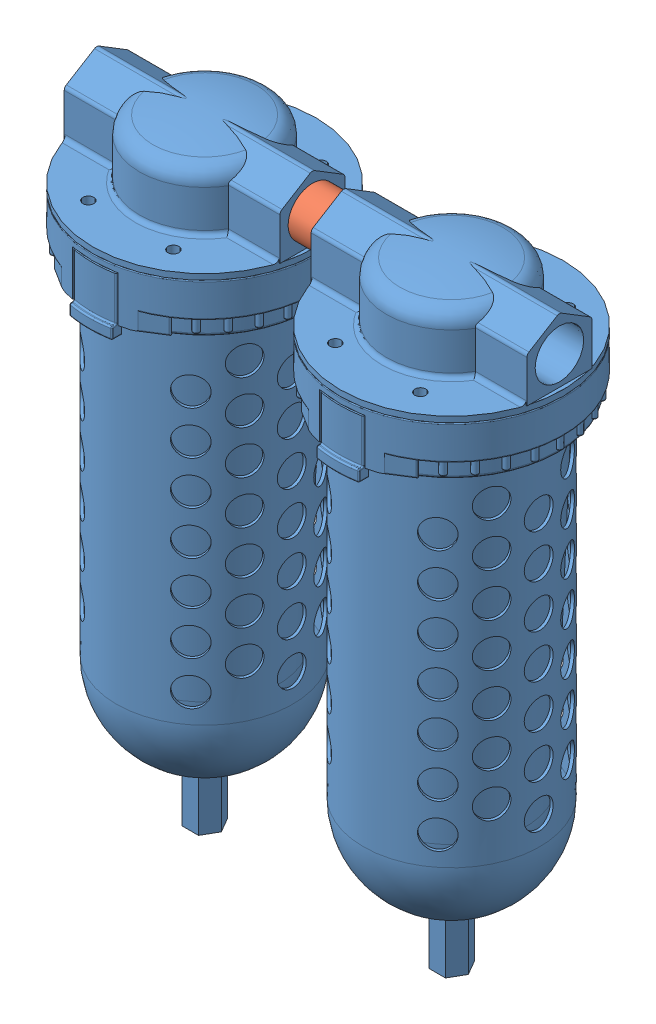
SolidWorks assembly ReadingTech_4P-060-P04-DC, configuration Default. Lengths in mm.
Overall size (206.63 271.66 99.95).
3 component instances, 2 part files, 3 mates.
Components (placement in the parent):
- ReadingTech_3P060P04F-1: ReadingTech_3P060P04F [Default] at (-33.0064 -72.8295 0.9918) size (98.17 271.66 99.95)
- ReadingTech_3P060P04F-2: ReadingTech_3P060P04F [Default] at (75.4516 -72.8295 0.9918) size (98.17 271.66 99.95)
- ReadingTech- 60cfm_connector_.5in-1: ReadingTech- 60cfm_connector_.5in [Default] at (28.0806 143.0705 0.9918) x (0 1 0) z (0 0 1) size (21.34 13.72 21.34)
Mates (geometry in assembly coordinates):
- Coincident1: coincident anti-aligned: circle of ReadingTech_3P060P04F-1; circle of ReadingTech- 60cfm_connector_.5in-1
- Coincident2: coincident aligned: circle of ReadingTech_3P060P04F-2; circle of ReadingTech- 60cfm_connector_.5in-1
- Coincident3: coincident aligned: plane of ReadingTech_3P060P04F-1 through (14.3646 130.3705 15.2793) normal (0 0 1); plane of ReadingTech_3P060P04F-2 through (122.8226 130.3705 15.2793) normal (0 0 1)
